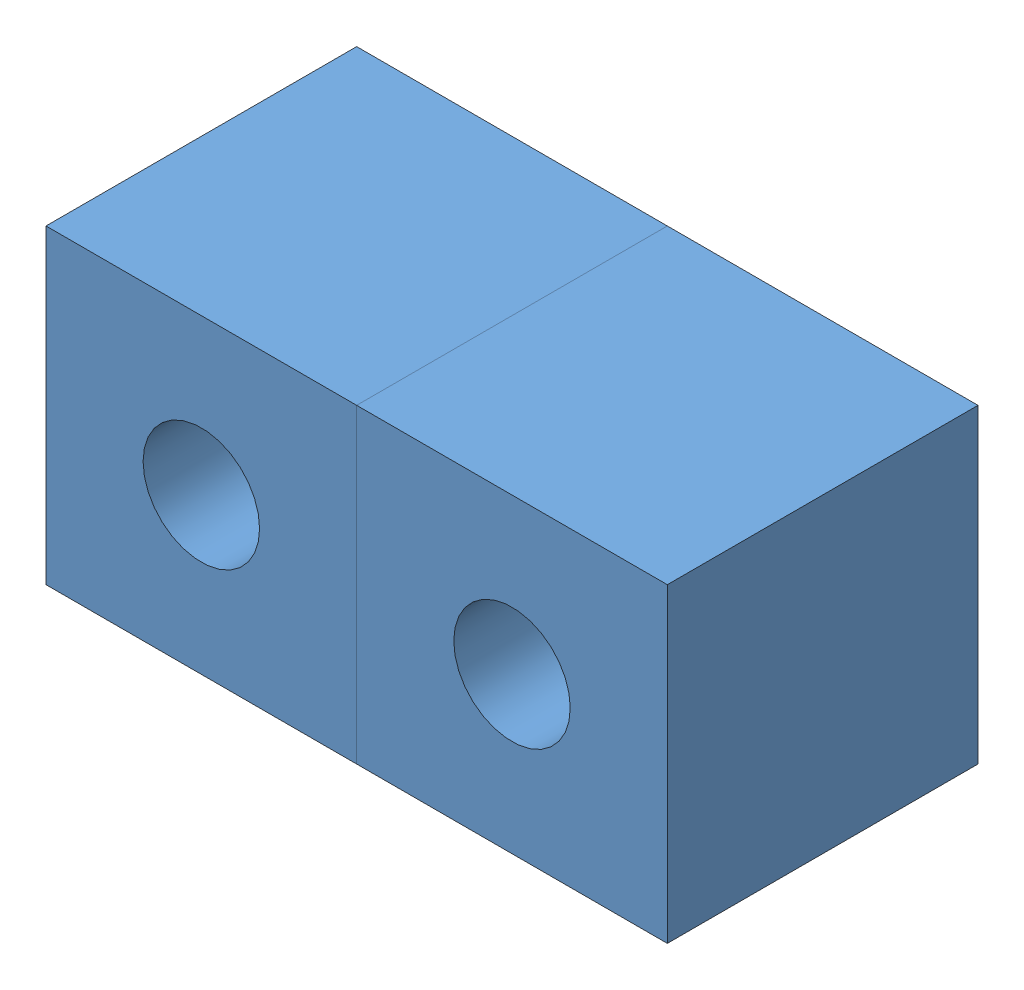
SolidWorks assembly Blocks, configuration Default. Lengths in mm.
Overall size (2032 1016 1016).
2 component instances, 1 part files, 6 mates.
Components (placement in the parent):
- example-1: example [Default] at (-508.001 0 0) size (1016 1016 1016)
- example-2: example [Default] at (508.001 0 0) size (1016 1016 1016)
Mates (geometry in assembly coordinates):
- Coincident1: coincident aligned: plane of example-1 through (0 -508.001 508) normal (1 0 0)
- Coincident2: coincident aligned: plane of example-1 through (-508.001 0 0) normal (0 0 1)
- Coincident4: coincident aligned: plane of example-1 through (-508.001 0 0) normal (0 1 0)
- Coincident5: coincident anti-aligned: plane of example-2 through (0 -508.001 508) normal (-1 0 0)
- Coincident6: coincident aligned: plane of example-2 through (508.001 0 0) normal (0 0 1)
- Coincident7: coincident aligned: plane of example-2 through (508.001 0 0) normal (0 1 0)
